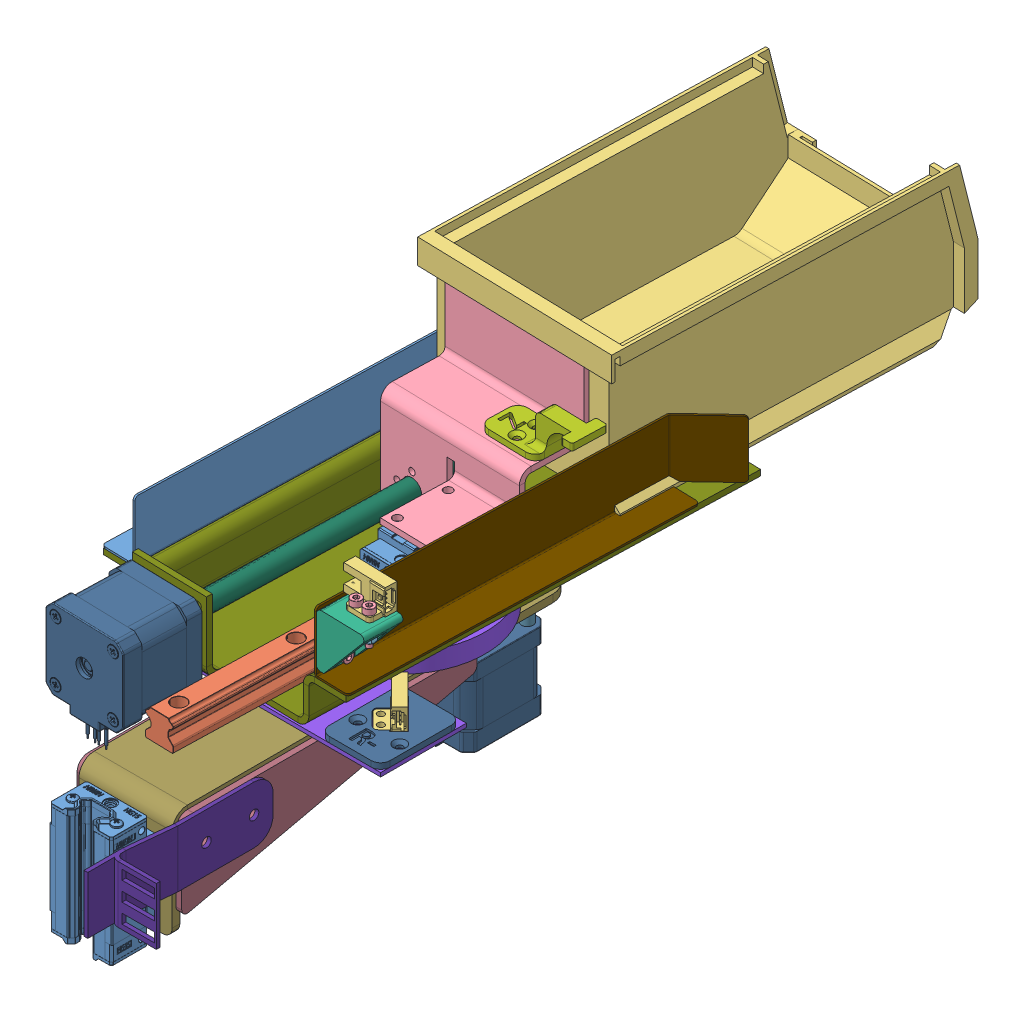
SolidWorks assembly T00003-000-R00, configuration Default. Lengths in mm.
Overall size (146.34 185.95 438.31).
45 component instances, 28 part files, 236 mates.
Components (placement in the parent):
- T00108-E00-R00-3: T00108-E00-R00 [Default] at (157.9488 862.2474 269.7743) x (1 0 0) z (0 1 0) size (34 23.7 61.49)
- T00110-E00-R00-1: T00110-E00-R00 [HGR15R400CE20] at (179.5179 918.7474 -31.6814) x (-0.999622 0 -0.027507) z (0.027507 0 -0.999622) size (15 15 270)
- T00108-E00-R00-4: T00108-E00-R00 [Default] at (176.1354 919.5474 91.2378) x (-0.999622 0 -0.027507) z (0.027507 0 -0.999622) size (34 23.7 61.49)
- T00148-E00-R00-1: T00148-E00-R00 [Default] at (211.9326 941.2474 40.4812) x (-0.999622 0 -0.027507) z (0.027507 0 -0.999622) size (104.77 76.2 187.32)
- T00126-000-R00-1: T00126-000-R00 [Default] at (176.1354 950.5474 91.2378) x (-0.999622 0 -0.027507) z (0 1 0) size (75 74 94)
- T00127-E00-R00-1: T00127-E00-R00 [DIN 625 - 6002 - 12,SI,NC,12_68] at (157.9488 901.2474 97.7743) x (0 1 0) z (0 0 1) size (9 32 32)
- T00128-0A4-R00-1: T00128-0A4-R00 [Default] at (157.9488 887.7474 97.7743) x (1 0 0) z (0 -1 0) size (25 25 21)
- T00129-E00-R00-1: T00129-E00-R00 [Circlip DIN 471 - 15 x 1.5] at (157.9488 905.9474 97.7743) x (0.837169 0 0.546944) z (0 -1 0) size (17.74 21.49 1.5)
- T00130-0A4-R01-1: T00130-0A4-R01 [Default] at (157.9488 895.7474 97.7743) x (0.027507 0 -0.999622) z (0 -1 0) size (90 90 20)
- T00132-E00-R00-4: T00132-E00-R00 [Metric - Spur gear 1M 60T 20PA 9FW ---S60N75H50L42N] at (157.9488 896.7474 97.7743) x (0 1 0) z (0 0 1) size (9 61.95 61.95)
- T00107-E00-R00-1: T00107-E00-R00 [Varsayılan] at (157.9488 879.7474 61.7743) x (-1 0 0) z (0 1 0) size (42 58.5 65.65)
- T00131-E00-R00-2: T00131-E00-R00 [Metric - Spur gear 1M 12T 20PA 8FW ---S12O10H14L5N] at (157.9488 896.7474 61.7743) x (0 1 0) z (0.924225 0 0.381849) size (14 13.61 13.61)
- T00133-0A4-R00-3: T00133-0A4-R00 [Default] at (157.9488 862.2474 237.7743) x (1 0 0) z (0 1 0) size (49 210 57)
- T00134-DXF-R00-1: T00134-DXF-R00 [Default] at (130.4488 892.7474 239.7743) x (0 0 -1) z (-1 0 0) size (155 44.25 3)
- T00134-DXF-R00-2: T00134-DXF-R00 [Default] at (182.4488 892.7474 239.7743) x (0 0 -1) z (-1 0 0) size (155 44.25 3)
- T00105-E00-R00-1: T00105-E00-R00 [Default] at (142.4488 890.7474 46.2743) x (1 0 0) z (0 -1 0) size (6 6 11)
- T00105-E00-R00-2: T00105-E00-R00 [Default] at (173.4488 890.7474 46.2743) x (0.974973 0 -0.222324) z (0 -1 0) size (6 6 11)
- T00105-E00-R00-3: T00105-E00-R00 [Default] at (142.4488 890.7474 77.2743) x (1 0 0) z (0 -1 0) size (6 6 11)
- T00105-E00-R00-4: T00105-E00-R00 [Default] at (173.4488 890.7474 77.2743) x (1 0 0) z (0 -1 0) size (6 6 11)
- T00107-E00-R00-2: T00107-E00-R00 [Varsayılan] at (132.7203 933.2474 196.6177) x (0.999622 0 0.027507) z (0.027507 0 -0.999622) size (42 58.5 65.65)
- T00111-E00-R00-1: T00111-E00-R00 [Default] at (139.377 933.2474 -45.2907) x (0.577812 0.816015 0.0159) z (0.815706 -0.578031 0.022446) size (10 240 10)
- T00135-DXF-R01-1: T00135-DXF-R01 [Default] at (158.3614 918.7474 82.78) x (-0.027507 0 0.999622) z (-0.999622 0 -0.027507) size (219 39 131)
- T00136-DXF-R01-1: T00136-DXF-R01 [Default] at (187.4488 877.7474 233.7743) x (0 0 -1) z (1 0 0) size (94.88 30 25)
- T00137-000-R00-1: T00137-000-R00 [gespiegeld] at (209.9194 941.2474 8.6701) x (0.027507 0 -0.999622) z (0.999622 0 0.027507) size (201.93 32 21.92)
- T00138-000-R00-1: T00138-000-R00 [gespiegeld] at (111.9565 941.2474 5.9745) x (0.027507 0 -0.999622) z (0.999622 0 0.027507) size (201.93 32 21.92)
- T00162-03D-R00-1: T00162-03D-R00 [Default] at (157.9488 905.7474 97.7743) x (0.027507 0 -0.999622) z (0 -1 0) size (22 26.53 4.1)
- T00153-E00-R00-4: T00153-E00-R00 [Default] at (207.435 977.2474 171.6635) x (0.027507 0 -0.999622) z (0 1 0) size (13 22.4 13.7)
- socket head cap screw_iso-1: socket head cap screw_iso [ISO 4762 M3 x 16 - 16N] at (223.2364 978.7474 179.1009) x (0 -1 0) z (0.997971 0 0.063667) size (19 5.5 5.5)
- hex nut style 1 gradeab_iso-1: hex nut style 1 gradeab_iso [ISO - 4032 - M3 - W - N] at (223.2364 965.2474 179.1009) x (1 0 0) z (0 1 0) size (5.5 6.35 2.4)
- socket head cap screw_iso-2: socket head cap screw_iso [ISO 4762 M3 x 16 - 16N] at (216.2391 978.7474 178.9084) x (0 -1 0) z (0 0 1) size (19 5.5 5.5)
- socket head cap screw_iso-3: socket head cap screw_iso [ISO 4762 M3 x 8 - 8N] at (212.2406 949.2474 178.7984) x (-0.999622 0 -0.027507) z (0.027393 0.090831 -0.995489) size (11 5.5 5.5)
- socket head cap screw_iso-4: socket head cap screw_iso [ISO 4762 M3 x 8 - 8N] at (212.2406 957.2474 178.7984) x (-0.999622 0 -0.027507) z (0.020371 -0.671964 -0.740304) size (11 5.5 5.5)
- hex nut style 1 gradeab_iso-3: hex nut style 1 gradeab_iso [ISO - 4032 - M3 - W - N] at (216.2391 965.4397 178.9084) x (0.95019 0 0.311672) z (0 1 0) size (5.5 6.35 2.4)
- hex nut style 1 gradeab_iso-4: hex nut style 1 gradeab_iso [ISO - 4032 - M3 - W - N] at (204.2436 957.2474 178.5783) x (0.020371 -0.671964 -0.740304) z (0.999622 0 0.027507) size (5.5 6.35 2.4)
- hex nut style 1 gradeab_iso-5: hex nut style 1 gradeab_iso [ISO - 4032 - M3 - W - N] at (204.2436 949.2474 178.5783) x (0.020371 -0.671964 -0.740304) z (0.999622 0 0.027507) size (5.5 6.35 2.4)
- socket head cap screw_iso-8: socket head cap screw_iso [ISO 4762 M4 x 10 - 10N] at (158.994 897.7474 59.7887) x (0 1 0) z (0.50631 0 0.862351) size (14 7 7)
- T00153-E00-R00-7: T00153-E00-R00 [Default] at (120.7549 900.9974 134.9681) x (0.707107 0 0.707107) z (0 1 0) size (13 22.4 13.7)
- T00153-E00-R00-8: T00153-E00-R00 [Default] at (195.1426 900.9974 134.9681) x (0.707107 0 -0.707107) z (0 1 0) size (13 22.4 13.7)
- socket head cap screw_iso-11: socket head cap screw_iso [ISO 4762 M3 x 6 - 6N] at (168.9902 898.7474 60.0638) x (0 1 0) z (0 0 1) size (9 5.5 5.5)
- socket head cap screw_iso-13: socket head cap screw_iso [ISO 4762 M3 x 6 - 6N] at (148.9978 898.7474 59.5136) x (0 1 0) z (-0.359477 0 -0.933154) size (9 5.5 5.5)
- T00168-03D-R00-2: T00168-03D-R00 [Default] at (205.2432 959.2474 178.6058) x (0.027507 0 -0.999622) z (0.999622 0 0.027507) size (20 28 25.65)
- T00163-03D-R00-1: T00163-03D-R00 [Default] at (179.6935 970.5474 52.8211) x (0.999622 0 0.027507) z (0 1 0) size (49 20 18.45)
- T00161-0A4-R00-2: T00161-0A4-R00 [Default] at (157.9488 894.7474 147.7835) size (125 2 45)
- T00164-03D-R00-1: T00164-03D-R00 [Default] at (157.9488 896.7474 147.7835) x (1 0 0) z (0 1 0) size (32 42.2 3)
- T00165-03D-R00-1: T00165-03D-R00 [Default] at (250.9488 896.7474 147.7835) x (1 0 0) z (0 1 0) size (32 42.2 3)
Mates (geometry in assembly coordinates):
- Coincident1: coincident: plane of ? through (170.4488 216.5018 364.6743) normal (1 0 0); plane of ? through (170.4488 228.5018 34.6743) normal (-1 0 0)
- Coincident2: coincident: plane of ? through (148.4488 238.5018 364.6743) normal (0 1 0); plane of ? through (170.4488 238.5018 394.6743) normal (0 1 0)
- Coincident3: coincident: plane of ? through (145.4488 216.5018 364.6743) normal (-1 0 0); plane of ? through (145.4488 223.5018 394.6743) normal (1 0 0)
- Coincident4: coincident: plane of ? through (148.4488 213.5018 364.6743) normal (0 -1 0); plane of ? through (142.4488 213.5018 34.6743) normal (0 -1 0)
- Coincident5: coincident: plane of ? through (142.4488 228.5018 404.6743) normal (0 0 1); plane of ? through (170.4488 223.5018 404.6743) normal (0 0 1)
- Width1: width: plane of ? through (142.4488 228.5018 404.6743) normal (0 0 1); plane of ? through (142.4488 228.5018 24.6743) normal (0 0 -1); plane of ? through (148.4488 216.5018 64.6743) normal (0 0 -1); plane of ? through (148.4488 216.5018 364.6743) normal (0 0 1)
- Concentric1: concentric: cylinder of ? through (142.4488 226.0018 394.6743) axis (1 0 0) radius 3.25; cylinder of ? through (157.9488 226.0018 394.6743) axis (-1 0 0) radius 3
- Concentric2: concentric: cylinder of ? through (142.4488 226.0018 34.6743) axis (1 0 0) radius 3.25; cylinder of ? through (157.9488 226.0018 34.6743) axis (-1 0 0) radius 3
- Width2: width: plane of ? through (168.9488 223.0018 34.6743) normal (1 0 0); plane of ? through (146.9488 219.0018 34.6743) normal (-1 0 0); plane of ? through (145.4488 223.5018 394.6743) normal (1 0 0); plane of ? through (170.4488 228.5018 34.6743) normal (-1 0 0)
- Width3: width: plane of ? through (168.9488 223.0127 394.9296) normal (1 0 0); plane of ? through (146.9488 219.0272 395.2699) normal (-1 0 0); plane of ? through (142.4488 223.5018 394.6743) normal (-1 0 0); plane of ? through (173.4488 228.5018 34.6743) normal (1 0 0)
- Tangent1: tangent: cylinder of ? through (157.9488 226.0018 -111.0344) axis (-1 0 0) radius 25; plane of ? through (135.9488 201.0018 1171.0489) normal (0 1 0)
- Tangent2: tangent: cylinder of ? through (157.9488 226.0018 -471.0344) axis (-1 0 0) radius 25; plane of ? through (135.9488 201.0018 1171.0489) normal (0 1 0)
- Width4: width: plane of ? through (173.4488 228.5018 -471.0344) normal (1 0 0); plane of ? through (142.4488 223.5018 -111.0344) normal (-1 0 0); plane of ? through (179.9488 201.0018 1171.0489) normal (-1 0 0); plane of ? through (135.9488 201.0018 1171.0489) normal (1 0 0)
- Width9: width: plane of ? through (172.9488 242.5018 314.4743) normal (1 0 0); plane of ? through (142.9488 242.5018 274.8743) normal (-1 0 0); plane of ? through (142.4488 223.5018 394.6743) normal (-1 0 0); plane of ? through (173.4488 228.5018 34.6743) normal (1 0 0)
- Coincident16: coincident: plane of ? through (148.1488 242.5018 269.6743) normal (0 0 -1); plane of ? through (150.9488 242.5018 269.6743) normal (0 0 1)
- Width10: width: plane of ? through (150.4488 833.0474 258.1086) normal (1 0 0); plane of ? through (165.4488 833.0474 258.1086) normal (-1 0 0); plane of ? through (150.4488 242.5018 258.0086) normal (-1 0 0); plane of ? through (165.4488 242.5018 258.0086) normal (1 0 0)
- Coincident18: coincident: plane of ? through (152.9073 834.5474 254.6743) normal (0 0 1); plane of ? through (162.9488 242.5018 254.6743) normal (0 0 -1)
- Width11: width: plane of ? through (172.9488 242.5018 314.4743) normal (1 0 0); plane of ? through (142.9488 242.5018 274.8743) normal (-1 0 0); plane of ? through (150.4488 242.5018 269.1743) normal (-1 0 0); plane of ? through (165.4488 242.5018 269.1743) normal (1 0 0)
- Coincident23: coincident: plane of T00110-E00-R00-1; plane of ? through (70.8326 930.4131 121.9122) normal (0.01567 0 -0.999877)
- Coincident24: coincident: plane of T00110-E00-R00-1 through (17.7623 933.7474 108.579) normal (0 1 0); plane of ? through (70.8718 933.7474 119.4125) normal (0 -1 0)
- Concentric5: concentric: circle of ?; cylinder of T00126-000-R00-1 through (87.3518 946.5474 101.6686) axis (0 1 0) radius 2.25
- Concentric6: concentric: circle of ?; cylinder of T00126-000-R00-1 through (86.9444 946.5474 127.6654) axis (0 1 0) radius 2.25
- Concentric8: concentric: cylinder of T00127-E00-R00-1 through (157.9488 880.6099 97.7743) axis (0 1 0) radius 7.5; cylinder of T00128-0A4-R00-1 through (157.9488 887.7474 97.7743) axis (0 -1 0) radius 7.5
- Coincident29: coincident: plane of T00127-E00-R00-1 through (147.8988 896.7474 97.7743) normal (0 -1 0); plane of T00128-0A4-R00-1 through (167.9488 896.7474 97.7743) normal (0 1 0)
- Concentric9: concentric: cylinder of T00128-0A4-R00-1 through (157.9488 887.7474 97.7743) axis (0 -1 0) radius 7.15; cylinder of T00129-E00-R00-1 through (157.9488 907.4474 97.7743) axis (0 -1 0) radius 7.15
- Coincident30: coincident: plane of T00128-0A4-R00-1 through (165.4488 905.9474 97.7743) normal (0 1 0); plane of T00129-E00-R00-1 through (157.9488 905.9474 97.7743) normal (0 -1 0)
- Concentric10: concentric: cylinder of T00127-E00-R00-1 through (157.9488 880.6099 97.7743) axis (0 1 0) radius 16; cylinder of T00130-0A4-R01-1 through (157.9488 895.7474 97.7743) axis (0 1 0) radius 16
- Coincident31: coincident: plane of T00127-E00-R00-1 through (142.2488 905.7474 97.7743) normal (0 1 0); plane of T00130-0A4-R01-1 through (158.3889 905.7474 81.7804) normal (0 -1 0)
- Concentric11: concentric: cylinder of T00130-0A4-R01-1 through (157.9488 895.7474 97.7743) axis (0 1 0) radius 21; cylinder of T00132-E00-R00-4 through (157.9488 946.7475 97.7743) axis (0 -1 0) radius 21
- Coincident32: coincident: plane of T00130-0A4-R01-1 through (158.5264 905.7474 76.7822) normal (0 -1 0); plane of T00132-E00-R00-4 through (157.9488 905.7474 97.7743) normal (0 1 0)
- Concentric12: concentric: cylinder of T00107-E00-R00-1 through (157.9488 904.7474 61.7743) axis (0 -1 0) radius 2.5; cylinder of T00131-E00-R00-2 through (157.9488 910.7475 61.7743) axis (0 -1 0) radius 2.5
- Coincident33: coincident: plane of T00107-E00-R00-1 through (159.9488 904.7474 61.7743) normal (0 1 0); plane of T00131-E00-R00-2 through (157.9488 904.7474 61.7743) normal (0 1 0)
- Distance5: distance = 1 mm: plane of T00131-E00-R00-2 through (157.9488 904.7474 61.7743) normal (0 1 0); plane of T00130-0A4-R01-1 through (158.5264 905.7474 76.7822) normal (0 -1 0)
- Coincident34: coincident: plane of T00108-E00-R00-3 through (173.9488 881.9474 241.7743) normal (0 0 -1); plane of T00133-0A4-R00-3 through (157.9488 862.2474 241.7743) normal (0 0 1)
- Concentric13: concentric: cylinder of T00108-E00-R00-3 through (144.9488 875.2474 241.7743) axis (0 0 -1) radius 1.65; cylinder of T00133-0A4-R00-3 through (144.9488 875.2474 241.7743) axis (0 0 -1) radius 2
- Concentric14: concentric: circle of T00108-E00-R00-3; cylinder of T00133-0A4-R00-3 through (170.9488 849.2474 241.7743) axis (0 0 -1) radius 2
- Coincident35: coincident: plane of T00128-0A4-R00-1 through (170.4488 890.7474 97.7743) normal (0 1 0); plane of T00133-0A4-R00-3 through (157.9488 890.7474 237.7743) normal (0 -1 0)
- Concentric15: concentric: cylinder of T00128-0A4-R00-1 through (157.9488 887.7474 97.7743) axis (0 -1 0) radius 12.5; cylinder of T00133-0A4-R00-3 through (157.9488 900.7474 97.7743) axis (0 -1 0) radius 10
- Concentric16: concentric: cone of T00107-E00-R00-1 through (142.4488 879.7474 46.2743) axis (0 -1 0); cylinder of T00133-0A4-R00-3 through (142.4488 894.7474 46.2743) axis (0 -1 0) radius 1.75
- Concentric17: concentric: circle of T00107-E00-R00-1; cylinder of T00133-0A4-R00-3 through (173.4488 894.7474 77.2743) axis (0 -1 0) radius 1.75
- Distance6: distance = 2 mm: plane of T00134-DXF-R00-2 through (185.4488 892.7474 233.7743) normal (0 1 0); plane of T00133-0A4-R00-3 through (157.9488 894.7474 237.7743) normal (0 1 0)
- Distance7: distance = 2 mm: plane of T00133-0A4-R00-3 through (157.9488 862.2474 241.7743) normal (0 0 1); plane of T00134-DXF-R00-2 through (185.4488 851.5004 239.7743) normal (0 0 1)
- Coincident39: coincident: plane of T00133-0A4-R00-3 through (182.4488 894.7474 31.7743) normal (1 0 0); plane of T00134-DXF-R00-2 through (182.4488 886.7474 233.7743) normal (-1 0 0)
- Coincident40: coincident: plane of T00133-0A4-R00-3 through (133.4488 894.7474 237.7743) normal (-1 0 0); plane of T00134-DXF-R00-1 through (133.4488 886.7474 233.7743) normal (1 0 0)
- Distance8: distance = 2 mm: plane of T00134-DXF-R00-1 through (133.4488 851.5004 239.7743) normal (0 0 1); plane of T00133-0A4-R00-3 through (157.9488 862.2474 241.7743) normal (0 0 1)
- Distance9: distance = 2 mm: plane of T00133-0A4-R00-3 through (157.9488 894.7474 237.7743) normal (0 1 0); plane of T00134-DXF-R00-1 through (133.4488 892.7474 233.7743) normal (0 1 0)
- Concentric18: concentric: cylinder of T00133-0A4-R00-3 through (173.4488 894.7474 46.2743) axis (0 -1 0) radius 1.75; cylinder of T00105-E00-R00-2 through (173.4488 879.7474 46.2743) axis (0 1 0) radius 1.75
- Coincident43: coincident: plane of T00107-E00-R00-1 through (157.9488 879.7474 61.7743) normal (0 1 0); plane of T00105-E00-R00-2 through (173.4488 879.7474 46.2743) normal (0 -1 0)
- Coincident44: coincident: plane of T00133-0A4-R00-3 through (157.9488 890.7474 237.7743) normal (0 -1 0); plane of T00105-E00-R00-1 through (142.4488 890.7474 46.2743) normal (0 1 0)
- Concentric19: concentric: cylinder of T00133-0A4-R00-3 through (142.4488 894.7474 46.2743) axis (0 -1 0) radius 1.75; cylinder of T00105-E00-R00-1 through (142.4488 879.7474 46.2743) axis (0 1 0) radius 1.75
- Coincident45: coincident: plane of T00133-0A4-R00-3 through (157.9488 890.7474 237.7743) normal (0 -1 0); plane of T00105-E00-R00-3 through (142.4488 890.7474 77.2743) normal (0 1 0)
- Concentric20: concentric: cylinder of T00133-0A4-R00-3 through (142.4488 894.7474 77.2743) axis (0 -1 0) radius 1.75; cylinder of T00105-E00-R00-3 through (142.4488 879.7474 77.2743) axis (0 1 0) radius 1.75
- Coincident46: coincident: plane of T00133-0A4-R00-3 through (157.9488 890.7474 237.7743) normal (0 -1 0); plane of T00105-E00-R00-4 through (173.4488 890.7474 77.2743) normal (0 1 0)
- Concentric21: concentric: cylinder of T00133-0A4-R00-3 through (173.4488 894.7474 77.2743) axis (0 -1 0) radius 1.75; cylinder of T00105-E00-R00-4 through (173.4488 879.7474 77.2743) axis (0 1 0) radius 1.75
- Coincident49: coincident: plane of T00110-E00-R00-1 through (165.5934 921.8332 238.0377) normal (-0.027507 0 0.999622); plane of T00107-E00-R00-2 through (131.6063 933.2474 237.1024) normal (-0.027507 0 0.999622)
- Concentric22: concentric: cylinder of T00107-E00-R00-2 through (133.408 933.2474 171.6272) axis (-0.027507 0 0.999622) radius 2.5; cylinder of T00111-E00-R00-1 through (133.6006 933.2474 164.6299) axis (-0.027507 0 0.999622) radius 2.5
- Coincident51: coincident: plane of T00107-E00-R00-2 through (132.7754 933.2474 194.6185) normal (0.027507 0 -0.999622); plane of T00111-E00-R00-1 through (132.7754 933.2474 194.6185) normal (-0.027507 0 0.999622)
- Coincident52: coincident: plane of T00130-0A4-R01-1 through (159.1866 915.7474 52.7913) normal (0 1 0); plane of T00135-DXF-R01-1 through (158.3614 915.7474 82.78) normal (0 -1 0)
- Coincident53: coincident: plane of T00110-E00-R00-1 through (179.0883 918.7474 238.409) normal (0 -1 0); plane of T00135-DXF-R01-1 through (158.3614 918.7474 82.78) normal (0 1 0)
- Distance11: distance = 3 mm: plane of T00107-E00-R00-2 through (132.7203 933.2474 196.6177) normal (0.027507 0 -0.999622); plane of T00135-DXF-R01-1 through (155.2943 918.7474 194.2378) normal (-0.027507 0 0.999622)
- Concentric23: concentric: cylinder of T00107-E00-R00-2 through (117.2262 948.7474 196.1914) axis (0.027507 0 -0.999622) radius 1.25; cylinder of T00135-DXF-R01-1 through (123.3327 948.7474 -25.7246) axis (-0.027507 0 0.999622) radius 1.75
- Concentric24: concentric: cylinder of T00107-E00-R00-2 through (148.2145 948.7474 197.0441) axis (0.027507 0 -0.999622) radius 1.25; cylinder of T00135-DXF-R01-1 through (154.321 948.7474 -24.8719) axis (-0.027507 0 0.999622) radius 1.75
- Coincident55: coincident: plane of T00148-E00-R00-1 through (217.0854 941.2474 -146.7729) normal (0 -1 0); plane of T00135-DXF-R01-1 through (158.3614 941.2474 82.78) normal (0 1 0)
- Width12: width: plane of T00148-E00-R00-1 through (113.164 941.2474 37.7634) normal (-0.999622 0 -0.027507); plane of T00148-E00-R00-1 through (205.9659 941.2474 40.317) normal (0.999622 0 0.027507); plane of T00135-DXF-R01-1 through (220.9621 941.2474 189.0421) normal (0.999622 0 0.027507); plane of T00135-DXF-R01-1 through (90.0117 941.2474 185.4387) normal (-0.999622 0 -0.027507)
- Coincident56: coincident: plane of T00148-E00-R00-1 through (211.9826 1014.7804 38.7039) normal (0.027507 0 -0.999622); plane of T00126-000-R00-1 through (177.6071 950.5474 37.758) normal (-0.027507 0 0.999622)
- Coincident62: coincident: plane of ? through (148.4488 238.5018 364.6743) normal (0 1 0); plane of ? through (100.4488 238.5018 294.6743) normal (0 -1 0)
- Width15: width: plane of ? through (142.9488 242.5018 224.6743) normal (-1 0 0); plane of ? through (172.9488 242.5018 364.6743) normal (1 0 0); plane of ? through (142.4488 223.5018 394.6743) normal (-1 0 0); plane of ? through (173.4488 228.5018 34.6743) normal (1 0 0)
- Coincident63: coincident: plane of ? through (148.4488 216.5018 364.6743) normal (0 0 1); plane of ? through (57.9488 242.5018 364.6743) normal (0 0 1)
- Width16: width: plane of ? through (57.9488 242.5018 364.6743) normal (0 0 1); plane of ? through (57.9488 242.5018 224.6743) normal (0 0 -1); plane of ? through (148.1488 242.5018 269.6743) normal (0 0 -1); plane of ? through (167.7488 242.5018 319.6743) normal (0 0 1)
- Coincident64: coincident: plane of ? through (164.4488 242.5018 266.5885) normal (0 -1 0); plane of ? through (100.4488 242.5018 294.6743) normal (0 1 0)
- Coincident65: coincident: plane of ? through (167.7488 242.5018 314.4743) normal (0 -1 0); plane of ? through (100.4488 242.5018 294.6743) normal (0 1 0)
- Coincident70: coincident: plane of ? through (82.9488 242.5018 294.6743) normal (0 -1 0); plane of ? through (100.4488 242.5018 294.6743) normal (0 1 0)
- Concentric28: concentric: cylinder of ? through (82.9488 248.5018 339.6743) axis (0 1 0) radius 6; cylinder of ? through (82.9488 242.5018 339.6743) axis (0 -1 0) radius 6.25
- Concentric29: concentric: cylinder of ? through (82.9488 248.5018 249.6743) axis (0 1 0) radius 6; cylinder of ? through (82.9488 242.5018 249.6743) axis (0 -1 0) radius 6.25
- Coincident74: coincident: plane of T00130-0A4-R01-1 through (157.9488 895.7474 97.7743) normal (0.999622 0 0.027507); plane of T00135-DXF-R01-1 through (158.3614 918.7474 82.78) normal (-0.999622 0 -0.027507)
- Distance14: distance = 15 mm: plane of T00135-DXF-R01-1 through (158.3614 918.7474 82.78) normal (-0.027507 0 0.999622); plane of T00130-0A4-R01-1 through (157.9488 895.7474 97.7743) normal (0.027507 0 -0.999622)
- LimitDistance1: limit distance = 51.7728 mm: plane of ? through (69.531 925.1631 109.2402) normal (-0.999877 0 -0.01567); plane of T00110-E00-R00-1
- LimitAngle1: limit planar angle = 0 rad: plane of T00135-DXF-R01-1 through (203.8442 918.7474 84.0315) normal (0.999622 0 0.027507); plane of T00133-0A4-R00-3 through (133.4488 894.7474 31.7743) normal (0 0 -1)
- LimitDistance2: limit distance = 589.0457 mm: plane of ? through (100.4488 242.5018 294.6743) normal (0 1 0); plane of ? through (163.0988 831.5474 263.3586) normal (0 -1 0)
- LimitDistance3: limit distance = 1272.0833 mm: plane of ? through (170.4488 223.5018 -101.0344) normal (0 0 1); plane of ? through (157.9488 198.0018 1171.0489) normal (0 0 1)
- Coincident103: coincident: plane of ? through (132.9488 198.0018 1171.0489) normal (-1 0 0); plane of ? through (132.9488 203.0018 1171.0489) normal (-1 0 0)
- Coincident104: coincident: plane of ? through (157.9488 198.0018 1171.0489) normal (0 0 1); plane of ? through (137.9488 203.0018 1171.0489) normal (0 0 -1)
- Coincident105: coincident: plane of ? through (132.9488 198.0018 1171.0489) normal (0 -1 0); plane of ? through (137.9488 198.0018 1171.0489) normal (0 -1 0)
- Coincident106: coincident: plane of ? through (132.9488 198.0018 1171.0489) normal (-1 0 0); plane of ? through (132.9488 203.0018 -564.9511) normal (-1 0 0)
- Coincident107: coincident: plane of ? through (157.9488 198.0018 -560.9511) normal (0 0 -1); plane of ? through (137.9488 203.0018 -560.9511) normal (0 0 1)
- Coincident108: coincident: plane of ? through (132.9488 198.0018 1171.0489) normal (0 -1 0); plane of ? through (137.9488 198.0018 -564.9511) normal (0 -1 0)
- Distance26: distance = 1 mm: plane of ? through (117.9488 237.5018 249.6743) normal (0 1 0); plane of ? through (100.4488 238.5018 294.6743) normal (0 -1 0)
- Concentric55: concentric: circle of ?; cylinder of ? through (112.9488 234.0018 249.6743) axis (0 1 0) radius 11
- Coincident125: coincident: plane of ? through (123.9488 230.5018 249.6743) normal (0 -1 0); plane of ? through (117.9488 230.5018 249.6743) normal (0 1 0)
- Concentric56: concentric: cylinder of ? through (112.9488 234.0018 249.6743) axis (0 1 0) radius 11; cylinder of ? through (112.9488 227.0018 249.6743) axis (0 1 0) radius 11
- Distance27: distance = 1 mm: plane of ? through (108.7629 237.5018 336.9396) normal (0 1 0); plane of ? through (100.4488 238.5018 294.6743) normal (0 -1 0)
- Concentric57: concentric: cylinder of ? through (112.9488 242.5018 339.6743) axis (0 -1 0) radius 4.25; cylinder of ? through (112.9488 234.0018 339.6743) axis (0 -1 0) radius 11
- Coincident127: coincident: plane of ? through (108.7629 230.5018 336.9396) normal (0 -1 0); plane of ? through (103.7399 230.5018 333.6579) normal (0 1 0)
- Concentric58: concentric: cylinder of ? through (112.9488 234.0018 339.6743) axis (0 -1 0) radius 11; cylinder of ? through (112.9488 227.0018 339.6743) axis (0 -1 0) radius 11
- Concentric59: concentric: cylinder of ? through (82.9488 208.9018 -211.0344) axis (0 1 0) radius 7.5; cylinder of ? through (82.9488 1416.5905 -211.0344) axis (0 1 0) radius 7.5
- Distance28: distance = 1 mm: plane of ? through (105.5523 237.5018 -196.2669) normal (0 1 0); plane of ? through (100.4488 238.5018 -211.0344) normal (0 -1 0)
- Coincident133: coincident: plane of T00134-DXF-R00-2 through (185.4488 892.7474 233.7743) normal (0 1 0); plane of T00136-DXF-R01-1 through (185.4488 892.7474 273.7743) normal (0 1 0)
- Coincident134: coincident: plane of T00134-DXF-R00-2 through (185.4488 886.7474 233.7743) normal (1 0 0); plane of T00136-DXF-R01-1 through (185.4488 877.7474 233.7743) normal (-1 0 0)
- Concentric63: concentric: cylinder of T00134-DXF-R00-2 through (175.4488 877.7474 203.7743) axis (1 0 0) radius 2.75; cylinder of T00136-DXF-R01-1 through (185.4488 877.7474 203.7743) axis (1 0 0) radius 2.5
- Coincident135: coincident: plane of ? through (172.9488 242.5018 314.4743) normal (1 0 0); plane of ? through (172.9488 266.0484 296.2234) normal (-1 0 0)
- Concentric68: concentric: cylinder of ? through (209.3488 260.2518 294.6743) axis (1 0 0) radius 6; cylinder of ? through (-989.14 260.2518 294.6743) axis (-1 0 0) radius 7.5
- Distance33: distance = 17 mm: plane of ? through (189.9488 282.6397 279.5818) normal (-1 0 0); plane of ? through (172.9488 242.5018 314.4743) normal (1 0 0)
- Lock1: lock: unknown of ?; unknown of ?
- Coincident136: coincident: plane of T00110-E00-R00-1 through (179.0883 918.7474 238.409) normal (0 -1 0); plane of T00135-DXF-R01-1 through (158.3614 918.7474 82.78) normal (0 1 0)
- Concentric77: concentric: cylinder of T00126-000-R00-1 through (136.4897 933.2474 59.6353) axis (-0.027507 0 0.999622) radius 5.25; cylinder of T00111-E00-R00-1 through (132.7754 933.2474 194.6185) axis (0.027507 0 -0.999622) radius 5
- Coincident137: coincident: plane of T00135-DXF-R01-1 through (158.3614 941.2474 82.78) normal (0 1 0); plane of T00137-000-R00-1 through (209.9194 941.2474 8.6701) normal (0 -1 0)
- Distance34: distance = 1 mm: plane of T00135-DXF-R01-1 through (220.9621 941.2474 189.0421) normal (0.999622 0 0.027507); plane of T00137-000-R00-1 through (221.9617 941.2474 189.0696) normal (0.999622 0 0.027507)
- Distance35: distance = 32 mm: plane of T00137-000-R00-1 through (226.913 941.2474 9.1378) normal (0.027507 0 -0.999622); plane of T00135-DXF-R01-1 through (226.7936 941.2474 -22.8776) normal (0.027507 0 -0.999622)
- Coincident140: coincident: plane of T00135-DXF-R01-1 through (158.3614 941.2474 82.78) normal (0 1 0); plane of T00138-000-R00-1 through (111.9565 941.2474 5.9745) normal (0 -1 0)
- Distance36: distance = 1 mm: plane of T00135-DXF-R01-1 through (90.0117 941.2474 185.4387) normal (-0.999622 0 -0.027507); plane of T00138-000-R00-1 through (89.0121 941.2474 185.4112) normal (-0.999622 0 -0.027507)
- Distance37: distance = 32 mm: plane of T00138-000-R00-1 through (93.9633 941.2474 5.4793) normal (0.027507 0 -0.999622); plane of T00135-DXF-R01-1 through (95.8432 941.2474 -26.481) normal (0.027507 0 -0.999622)
- Concentric78: concentric: circle of T00108-E00-R00-4; cylinder of T00126-000-R00-1 through (162.7828 947.5474 103.8753) axis (0 1 0) radius 2.25
- Concentric80: concentric: circle of T00108-E00-R00-4; cylinder of T00126-000-R00-1 through (189.4881 947.5474 78.6003) axis (0 1 0) radius 2.25
- Coincident142: coincident: plane of T00108-E00-R00-4 through (160.6834 947.5474 71.1051) normal (0 1 0); plane of T00126-000-R00-1 through (176.1354 947.5474 91.2378) normal (0 -1 0)
- Width17: width: plane of T00108-E00-R00-4 through (180.0804 925.9631 120.5574) normal (-0.999622 0 -0.027507); plane of T00108-E00-R00-4 through (170.584 925.9631 120.2961) normal (0.999622 0 0.027507); plane of T00110-E00-R00-1 through (179.5881 919.2474 238.4228) normal (0.999622 0 0.027507); plane of T00110-E00-R00-1 through (164.5938 919.2474 238.0102) normal (-0.999622 0 -0.027507)
- Concentric81: concentric: circle of T00108-E00-R00-3; cylinder of T00133-0A4-R00-3 through (144.9488 875.2474 241.7743) axis (0 0 -1) radius 2
- Concentric82: concentric: circle of T00108-E00-R00-3; cylinder of T00133-0A4-R00-3 through (170.9488 849.2474 241.7743) axis (0 0 -1) radius 2
- Coincident144: coincident: plane of T00108-E00-R00-3 through (173.9488 881.9474 241.7743) normal (0 0 -1); plane of T00133-0A4-R00-3 through (157.9488 862.2474 241.7743) normal (0 0 1)
- Coincident145: coincident: plane of T00136-DXF-R01-1 through (182.9675 877.7474 233.6502) normal (-1 0 0); circle of ?
- Parallel1: parallel: line of T00136-DXF-R01-1 through (184.9675 892.7474 303.6502) axis (0 0 -1); line of ? through (182.9675 887.2474 281.5502) axis (0 0 1)
- Width18: width: plane of T00136-DXF-R01-1 through (184.9675 892.7474 303.6502) normal (0 0 1); plane of T00136-DXF-R01-1 through (184.9675 877.7474 275.6502) normal (0 0 1); plane of ? through (184.4675 900.2474 300.8502) normal (0 0 1); plane of ? through (180.7675 900.2474 278.4502) normal (0 0 -1)
- Distance38: distance = 1 mm: plane of ? through (182.0675 893.7474 286.7502) normal (0 -1 0); plane of T00136-DXF-R01-1 through (187.9675 892.7474 270.6502) normal (0 1 0)
- Coincident146: coincident: plane of T00136-DXF-R01-1 through (184.9675 877.7474 233.7743) normal (1 0 0); plane of ? through (184.9675 879.8974 301.3502) normal (-1 0 0)
- Distance39: distance = 19 mm: plane of T00136-DXF-R01-1 through (184.9675 877.7474 275.6502) normal (0 0 1); moEndPointRef_w of ?
- Parallel2: parallel: line of T00136-DXF-R01-1 through (184.9675 862.7474 303.6502) axis (0 1 0); line of ? through (184.9675 889.0974 301.3502) axis (0 -1 0)
- Width19: width: plane of T00136-DXF-R01-1 through (187.9675 862.7474 270.6502) normal (0 -1 0); plane of T00136-DXF-R01-1 through (187.9675 892.7474 270.6502) normal (0 1 0); plane of ? through (190.9675 889.0974 287.9502) normal (0 1 0); plane of ? through (187.4675 866.3974 301.3502) normal (0 -1 0)
- Coincident147: coincident: plane of T00133-0A4-R00-3 through (157.9488 894.7474 237.7743) normal (0 1 0); plane of ? through (132.9488 894.7474 61.7743) normal (0 -1 0)
- Width20: width: plane of T00133-0A4-R00-3 through (182.4488 894.7474 31.7743) normal (1 0 0); plane of T00133-0A4-R00-3 through (133.4488 894.7474 237.7743) normal (-1 0 0); plane of ? through (182.9488 894.7474 61.7743) normal (-1 0 0); plane of ? through (132.9488 894.7474 61.7743) normal (1 0 0)
- Coincident148: coincident: plane of T00133-0A4-R00-3 through (133.4488 894.7474 31.7743) normal (0 0 -1); plane of ? through (157.9488 894.7474 31.7743) normal (0 0 -1)
- InPlace1: in place: plane of ? through (178.9488 905.7474 97.7743) normal (0 -1 0); plane of ? through (0 905.7474 0) normal (0 -1 0); moOrthogonalPlaneRef_w of ? through (178.9488 905.7474 97.7743) normal (0 -1 0); plane of ? through (0 905.7474 0) normal (0 0 -1); plane of ? through (178.9488 905.7474 97.7743) normal (0 -1 0); plane of ? through (0 905.7474 0) normal (-1 0 0); plane of T00130-0A4-R01-1 through (158.5264 905.7474 76.7822) normal (0 -1 0); unknown of T00162-03D-R00-1
- Coincident153: coincident: plane of T00130-0A4-R01-1; plane of T00162-03D-R00-1
- Coincident154: coincident: line of T00130-0A4-R01-1 through (157.9488 905.7474 97.7743) axis (0.999622 0 0.027507); plane of T00162-03D-R00-1 through (157.9488 905.7474 97.7743) normal (0.999622 0 0.027507)
- Coincident155: coincident: unknown of T00130-0A4-R01-1; plane of T00162-03D-R00-1 through (157.9488 905.7474 97.7743) normal (0.027507 0 -0.999622)
- Coincident156: coincident: plane of T00130-0A4-R01-1 through (168.0287 905.7474 116.197) normal (0 -1 0); plane of ? through (157.9488 905.7474 97.7743) normal (0 1 0)
- Concentric83: concentric: cylinder of T00130-0A4-R01-1 through (139.9489 905.7474 64.8767) axis (0 -1 0) radius 2.1; cylinder of ? through (139.9489 901.7474 64.8767) axis (0 1 0) radius 2.25
- Coincident157: coincident: unknown of ?; unknown of ?
- InPlace2: in place: plane of T00134-DXF-R00-2 through (185.4488 886.7474 233.7743) normal (1 0 0); plane of ? through (185.4488 0 0) normal (1 0 0); plane of T00134-DXF-R00-2 through (185.4488 886.7474 233.7743) normal (1 0 0); plane of ? through (185.4488 0 0) normal (0 1 0); plane of T00134-DXF-R00-2 through (185.4488 886.7474 233.7743) normal (1 0 0); plane of ? through (185.4488 0 0) normal (0 0 -1); plane of T00134-DXF-R00-2 through (185.4488 886.7474 233.7743) normal (1 0 0); unknown of ?
- Coincident165: coincident: plane of T00134-DXF-R00-2; plane of ?
- Coincident166: coincident: plane of T00134-DXF-R00-2 through (185.4488 892.7474 239.7743) normal (0 -1 0); plane of ? through (185.4488 892.7474 239.7743) normal (0 -1 0)
- Coincident167: coincident: plane of T00134-DXF-R00-2 through (185.4488 892.7474 239.7743) normal (0 0 -1); plane of ? through (185.4488 892.7474 239.7743) normal (0 0 1)
- Coincident173: coincident: plane of T00134-DXF-R00-2 through (185.4488 886.7474 233.7743) normal (1 0 0); plane of ? through (185.4488 890.7474 97.2743) normal (-1 0 0)
- Distance44: distance = 15 mm: plane of T00134-DXF-R00-2 through (185.4488 889.7474 84.7743) normal (0 0 -1); plane of ? through (185.4488 879.7474 69.7743) normal (0 0 -1)
- Coincident175: coincident: plane of T00134-DXF-R00-2 through (185.4488 892.7474 233.7743) normal (0 1 0); plane of ? through (212.9488 892.7474 97.2743) normal (0 1 0)
- Width21: width: plane of ? through (240.4488 892.7474 124.7743) normal (0 0 1); plane of ? through (240.4488 892.7474 69.7743) normal (0 0 -1); plane of ? through (215.4488 896.9974 77.2743) normal (0 0 -1); plane of ? through (215.4488 896.9974 117.2743) normal (0 0 1)
- Coincident176: coincident: plane of ? through (212.9488 892.7474 97.2743) normal (0 1 0); plane of ? through (235.4488 892.7474 112.2743) normal (0 -1 0)
- Coincident177: coincident: plane of T00138-000-R00-1; plane of ? through (142.7292 957.2474 4.8288) normal (-0.746359 0 0.665543)
- Coincident178: coincident: plane of T00138-000-R00-1 through (255.8716 971.2474 131.7099) normal (0 1 0); plane of ? through (171.7754 971.2474 -7.6739) normal (0 1 0)
- Coincident179: coincident: plane of ? through (171.7754 971.2474 -7.6739) normal (0 1 0); plane of T00153-E00-R00-4 through (149.8068 971.2474 -14.8808) normal (0 -1 0)
- Width22: width: plane of ? through (171.7754 943.2474 -7.6739) normal (0.665543 0 0.746359); plane of ? through (158.4645 943.2474 -22.6011) normal (-0.665543 0 -0.746359); axis of ? through (154.8949 971.2474 -6.0195) axis (0 1 0)
- Concentric84: concentric: cylinder of T00153-E00-R00-4 through (223.2364 973.2474 179.1009) axis (0 1 0) radius 1.75; cylinder of socket head cap screw_iso-1 through (223.2364 1010.4974 179.1009) axis (0 1 0) radius 1.5
- Coincident182: coincident: plane of T00153-E00-R00-4 through (225.6107 975.7474 169.1625) normal (0 1 0); plane of socket head cap screw_iso-1 through (223.4115 975.7474 176.3565) normal (0 -1 0)
- Coincident183: coincident: plane of ? through (117.2278 963.2474 -29.7794) normal (0 -1 0); plane of hex nut style 1 gradeab_iso-1 through (154.8949 963.2474 -9.195) normal (0 1 0)
- Concentric85: concentric: cylinder of socket head cap screw_iso-1 through (223.2364 1010.4974 179.1009) axis (0 1 0) radius 1.5; cylinder of hex nut style 1 gradeab_iso-1 through (223.2364 962.8474 179.1009) axis (0 1 0) radius 1.25
- Coincident184: coincident: plane of T00153-E00-R00-4 through (225.6107 975.7474 169.1625) normal (0 1 0); plane of socket head cap screw_iso-2 through (218.9891 975.7474 178.9084) normal (0 -1 0)
- Concentric86: concentric: cylinder of T00153-E00-R00-4 through (216.2391 973.2474 178.9084) axis (0 1 0) radius 1.75; cylinder of socket head cap screw_iso-2 through (216.2391 1010.4974 178.9084) axis (0 1 0) radius 1.5
- Concentric87: concentric: cylinder of socket head cap screw_iso-2 through (216.2391 1010.4974 178.9084) axis (0 1 0) radius 1.5; cylinder of hex nut style 1 gradeab_iso-3 through (216.2391 963.0397 178.9084) axis (0 1 0) radius 1.25
- Coincident185: coincident: plane of ? through (117.2278 963.2474 -29.7794) normal (0 -1 0); plane of hex nut style 1 gradeab_iso-3 through (151.4071 963.2474 -4.0191) normal (0 1 0)
- Coincident186: coincident: plane of T00168-03D-R00-2 through (210.3761 965.2474 137.4904) normal (0.999622 0 0.027507); plane of socket head cap screw_iso-4 through (209.2926 959.284 176.8686) normal (-0.999622 0 -0.027507)
- Concentric88: concentric: cylinder of ? through (142.7292 955.2474 4.8288) axis (0.746359 0 -0.665543) radius 1.8; cylinder of socket head cap screw_iso-4 through (171.6506 955.2474 -20.961) axis (0.746359 0 -0.665543) radius 1.5
- Concentric91: concentric: cylinder of ? through (142.7292 947.2474 4.8288) axis (0.746359 0 -0.665543) radius 1.8; cylinder of socket head cap screw_iso-3 through (171.6506 947.2474 -20.961) axis (0.746359 0 -0.665543) radius 1.5
- Coincident187: coincident: plane of T00168-03D-R00-2 through (210.3761 965.2474 137.4904) normal (0.999622 0 0.027507); plane of socket head cap screw_iso-3 through (209.2348 951.9861 178.9655) normal (-0.999622 0 -0.027507)
- Coincident188: coincident: plane of T00137-000-R00-1 through (208.9198 941.2474 8.6426) normal (-0.999622 0 -0.027507); plane of hex nut style 1 gradeab_iso-4 through (204.3023 959.5991 176.4453) normal (0.999622 0 0.027507)
- Concentric92: concentric: cylinder of socket head cap screw_iso-4 through (243.9786 957.2474 179.6717) axis (0.999622 0 0.027507) radius 1.5; cylinder of hex nut style 1 gradeab_iso-4 through (201.8445 957.2474 178.5123) axis (0.999622 0 0.027507) radius 1.25
- Coincident189: coincident: plane of T00137-000-R00-1 through (208.9198 941.2474 8.6426) normal (-0.999622 0 -0.027507); plane of hex nut style 1 gradeab_iso-5 through (204.3023 951.5991 176.4453) normal (0.999622 0 0.027507)
- Concentric93: concentric: cylinder of socket head cap screw_iso-3 through (243.9786 949.2474 179.6717) axis (0.999622 0 0.027507) radius 1.5; circle of hex nut style 1 gradeab_iso-5
- Coincident190: coincident: plane of T00138-000-R00-1; plane of ? through (158.4645 943.2474 -22.6011) normal (-0.665543 0 -0.746359)
- Coincident191: coincident: plane of ? through (240.4488 892.7474 124.7743) normal (1 0 0); plane of ? through (240.4488 896.9974 112.2743) normal (1 0 0)
- Coincident192: coincident: plane of T00162-03D-R00-1 through (157.9488 901.7474 97.7743) normal (0 -1 0); plane of socket head cap screw_iso-8 through (155.9758 901.7474 61.5608) normal (0 1 0)
- Concentric94: concentric: cylinder of T00162-03D-R00-1 through (158.994 901.7474 59.7887) axis (0 1 0) radius 2.25; cylinder of socket head cap screw_iso-8 through (158.994 865.9974 59.7887) axis (0 -1 0) radius 2
- Distance43: distance = 52.5 mm: unknown of ?; line of T00127-E00-R00-1 through (157.9488 908.857 97.7743) axis (0 -1 0)
- Coincident196: coincident: plane of ? through (109.8842 896.9974 45.1603) normal (0 -1 0); plane of ? through (215.4488 896.9974 74.5623) normal (0 1 0)
- Symmetric1: symmetric: plane of ? through (117.4048 900.9974 54.123) normal (-0.766044 0 0.642788); plane of ? through (122.001 900.9974 50.2663) normal (0.766044 0 -0.642788)
- Width23: width: plane of T00162-03D-R00-1 through (157.9488 905.7474 97.7743) normal (0 1 0); plane of T00162-03D-R00-1 through (157.9488 902.2474 97.7743) normal (0 -1 0); plane of ? through (122.8042 906.9974 60.5578) normal (0 -1 0); plane of ? through (117.4048 900.9974 54.123) normal (0 1 0)
- Coincident199: coincident: plane of T00134-DXF-R00-2 through (185.4488 886.7474 233.7743) normal (1 0 0); plane of ? through (185.4488 890.7474 104.7743) normal (-1 0 0)
- Coincident201: coincident: plane of T00134-DXF-R00-2 through (185.4488 889.7474 84.7743) normal (0 0 -1); plane of ? through (185.4488 874.7474 84.7743) normal (0 0 -1)
- Coincident202: coincident: plane of ? through (215.4488 892.7474 74.5623) normal (0 -1 0); plane of ? through (212.9488 892.7474 104.7743) normal (0 1 0)
- Coincident203: coincident: plane of ? through (240.4488 896.9974 74.5623) normal (1 0 0); plane of ? through (240.4488 892.7474 124.7743) normal (1 0 0)
- Coincident206: coincident: plane of T00134-DXF-R00-1 through (130.4488 886.7474 233.7743) normal (-1 0 0); plane of ? through (130.4488 890.7474 104.7743) normal (1 0 0)
- Coincident207: coincident: plane of ? through (240.4488 892.7474 84.7743) normal (0 0 -1); plane of ? through (75.4488 892.7474 84.7743) normal (0 0 -1)
- Coincident208: coincident: plane of ? through (212.9488 892.7474 104.7743) normal (0 1 0); plane of ? through (102.9488 892.7474 104.7743) normal (0 1 0)
- Coincident209: coincident: plane of ? through (102.9488 892.7474 104.7743) normal (0 1 0); plane of ?
- Coincident210: coincident: plane of ? through (75.4488 892.7474 84.7743) normal (-1 0 0); plane of ?
- Coincident211: coincident: plane of ? through (75.4488 892.7474 84.7743) normal (0 0 -1); plane of ?
- Coincident212: coincident: plane of ? through (192.1446 889.9953 76.9058) normal (0.206766 0.946852 -0.246414); unknown of ?
- Symmetric2: symmetric: plane of ? through (131.1874 900.6377 134.3344) normal (0.766044 0 0.642788); plane of ? through (126.5912 900.6377 130.4777) normal (-0.766044 0 -0.642788)
- Distance46: distance = 52.2 mm: line of T00127-E00-R00-1 through (157.9488 908.857 97.7743) axis (0 -1 0); unknown of ?
- Width24: width: plane of T00162-03D-R00-1 through (157.9488 905.7474 97.7743) normal (0 1 0); plane of T00162-03D-R00-1 through (157.9488 902.2474 97.7743) normal (0 -1 0); plane of T00153-E00-R00-7 through (124.2905 906.9974 135.6752) normal (0 -1 0); plane of T00153-E00-R00-7 through (118.3508 900.9974 141.6149) normal (0 1 0)
- Symmetric3: symmetric: plane of T00153-E00-R00-7 through (114.1081 900.9974 137.3723) normal (-0.707107 0 -0.707107); plane of T00153-E00-R00-7 through (118.3508 900.9974 141.6149) normal (0.707107 0 0.707107)
- Distance47: distance = 52 mm: unknown of T00153-E00-R00-7; line of T00128-0A4-R00-1 through (157.9488 905.9474 97.7743) axis (0 -1 0)
- Width25: width: plane of T00153-E00-R00-8 through (201.7894 900.9974 137.3723) normal (0 1 0); plane of T00153-E00-R00-8 through (195.8497 906.9974 131.4326) normal (0 -1 0); plane of T00162-03D-R00-1 through (157.9488 905.7474 97.7743) normal (0 1 0); plane of T00162-03D-R00-1 through (157.9488 902.2474 97.7743) normal (0 -1 0)
- Symmetric4: symmetric: plane of T00153-E00-R00-8 through (201.7894 900.9974 137.3723) normal (0.707107 0 -0.707107); plane of T00153-E00-R00-8 through (197.5467 900.9974 141.6149) normal (-0.707107 0 0.707107)
- Distance48: distance = 52 mm: unknown of T00153-E00-R00-8; line of T00130-0A4-R01-1 through (157.9488 905.7474 97.7743) axis (0 1 0)
- InPlace3: in place: plane of ? through (157.9488 896.7474 148.0532) normal (0 1 0); plane of ? through (0 896.7474 0) normal (0 1 0); plane of ? through (157.9488 896.7474 148.0532) normal (0 1 0); plane of ? through (0 896.7474 0) normal (0 0 -1); plane of ? through (157.9488 896.7474 148.0532) normal (0 1 0); plane of ? through (0 896.7474 0) normal (1 0 0); plane of ? through (-456.6296 235.5306 -359.6309) normal (-0.293076 0.910062 -0.293076); unknown of ?
- Coincident214: coincident: plane of ?; plane of T00164-03D-R00-1
- Coincident215: coincident: unknown of ?; unknown of ?
- Coincident216: coincident: unknown of ?; unknown of ?
- Distance49: distance = 0.25 mm: plane of T00153-E00-R00-7 through (108.4513 897.2974 151.5144) normal (-0.707107 0 0.707107); plane of T00164-03D-R00-1 through (108.4513 899.7474 151.868) normal (0.707107 0 -0.707107)
- Coincident219: coincident: plane of ? through (-456.6296 235.5306 -359.6309) normal (-0.293076 0.910062 -0.293076); plane of T00165-03D-R00-1
- Coincident220: coincident: plane of ? through (-395.9284 247.2536 -383.9297) normal (0.044969 -0.293076 -0.955031); plane of T00165-03D-R00-1
- Coincident221: coincident: plane of ? through (-515.3072 210.6191 -378.3086) normal (-0.955031 -0.293076 0.044969); plane of T00165-03D-R00-1
- Concentric97: concentric: cylinder of T00161-0A4-R00-2 through (167.9488 886.7474 140.2835) axis (0 1 0) radius 2.25; cylinder of ? through (167.9488 932.4974 140.2835) axis (0 1 0) radius 3.5
- Coincident222: coincident: plane of T00161-0A4-R00-2; plane of ? through (171.4488 896.7474 140.2835) normal (0 -1 0)
- Coincident223: coincident: plane of T00153-E00-R00-8 through (211.6889 897.2974 147.2718) normal (0.707107 0 0.707107); plane of ? through (232.9394 911.031 126.0212) normal (-0.707107 0 -0.707107)
- Concentric98: concentric: cylinder of T00162-03D-R00-1 through (168.9902 901.7474 60.0638) axis (0 1 0) radius 1.75; cylinder of socket head cap screw_iso-11 through (168.9902 866.9974 60.0638) axis (0 -1 0) radius 1.5
- Coincident226: coincident: plane of T00162-03D-R00-1 through (157.9488 901.7474 97.7743) normal (0 -1 0); circle of socket head cap screw_iso-11
- Coincident229: coincident: plane of T00162-03D-R00-1 through (157.9488 901.7474 97.7743) normal (0 -1 0); plane of socket head cap screw_iso-13 through (151.564 901.7474 58.5251) normal (0 1 0)
- Concentric100: concentric: cylinder of T00162-03D-R00-1 through (148.9978 901.7474 59.5136) axis (0 1 0) radius 1.75; cylinder of socket head cap screw_iso-13 through (148.9978 866.9974 59.5136) axis (0 -1 0) radius 1.5
- Coincident230: coincident: plane of ? through (-456.6296 235.5306 -359.6309) normal (-0.293076 0.910062 -0.293076); plane of ? through (74.4309 575.6434 165.4295) normal (0.293076 -0.910062 0.293076)
- Concentric102: concentric: cylinder of ? through (147.9488 885.6615 140.2835) axis (0 1 0) radius 2.25; cylinder of ? through (60.6108 607.1524 155.1095) axis (-0.293076 0.910062 -0.293076) radius 2
- Coincident231: coincident: plane of ? through (-456.6296 235.5306 -359.6309) normal (-0.293076 0.910062 -0.293076); plane of ? through (55.3303 569.7819 166.3289) normal (0.293076 -0.910062 0.293076)
- Concentric103: concentric: cylinder of ? through (167.9488 885.6615 140.2835) axis (0 1 0) radius 2.25; cylinder of ? through (41.5102 601.2909 156.0088) axis (-0.293076 0.910062 -0.293076) radius 2
- Coincident232: coincident: plane of T00161-0A4-R00-2; plane of ? through (171.4488 896.7474 160.2835) normal (0 -1 0)
- Concentric104: concentric: cylinder of T00161-0A4-R00-2 through (167.9488 886.7474 160.2835) axis (0 1 0) radius 2.25; cylinder of ? through (167.9488 932.4974 160.2835) axis (0 1 0) radius 2
- Coincident233: coincident: plane of T00161-0A4-R00-2; plane of ? through (151.4488 896.7474 160.2835) normal (0 -1 0)
- Concentric105: concentric: cylinder of T00161-0A4-R00-2 through (147.9488 886.7474 160.2835) axis (0 1 0) radius 2.25; cylinder of ? through (147.9488 932.4974 160.2835) axis (0 1 0) radius 2
- Coincident234: coincident: plane of T00137-000-R00-1 through (209.9194 941.2474 8.6701) normal (0.999622 0 0.027507); plane of T00168-03D-R00-2 through (205.2432 959.2474 178.6058) normal (-0.999622 0 -0.027507)
- Coincident235: coincident: plane of T00137-000-R00-1 through (203.9685 941.2474 188.5745) normal (-0.027507 0 0.999622); plane of T00168-03D-R00-2 through (232.9576 945.2474 189.3722) normal (-0.027507 0 0.999622)
- Coincident236: coincident: plane of T00137-000-R00-1 through (208.9198 973.2474 8.6426) normal (0 1 0); plane of T00168-03D-R00-2 through (232.9576 973.2474 189.3722) normal (0 1 0)
- Coincident237: coincident: plane of T00153-E00-R00-4 through (225.6107 973.2474 169.1625) normal (0 -1 0); plane of T00168-03D-R00-2 through (232.9576 973.2474 189.3722) normal (0 1 0)
- Concentric113: concentric: cylinder of socket head cap screw_iso-1 through (223.2364 1010.4974 179.1009) axis (0 1 0) radius 1.5; cylinder of T00168-03D-R00-2 through (223.2364 963.2474 179.1009) axis (0 1 0) radius 1.9
- Concentric114: concentric: cylinder of socket head cap screw_iso-2 through (216.2391 1010.4974 178.9084) axis (0 1 0) radius 1.5; cylinder of T00168-03D-R00-2 through (216.2391 963.2474 178.9084) axis (0 1 0) radius 1.9
- Concentric115: concentric: cylinder of socket head cap screw_iso-4 through (243.9786 957.2474 179.6717) axis (0.999622 0 0.027507) radius 1.5; cylinder of T00168-03D-R00-2 through (205.2432 957.2474 178.6058) axis (0.999622 0 0.027507) radius 1.9
- Concentric116: concentric: cylinder of socket head cap screw_iso-3 through (243.9786 949.2474 179.6717) axis (0.999622 0 0.027507) radius 1.5; cylinder of T00168-03D-R00-2 through (205.2432 949.2474 178.6058) axis (0.999622 0 0.027507) radius 1.9
- Coincident238: coincident: plane of T00126-000-R00-1 through (176.1354 970.5474 91.2378) normal (0 1 0); plane of T00163-03D-R00-1 through (169.5598 970.5474 57.5441) normal (0 -1 0)
- Coincident241: coincident: plane of T00126-000-R00-1 through (195.1004 970.5474 38.2394) normal (0.999622 0 0.027507); plane of T00163-03D-R00-1 through (194.5503 973.5474 58.2318) normal (0.999622 0 0.027507)
- Symmetric5: symmetric: line of T00126-000-R00-1 through (194.3578 970.5474 65.2292) axis (-0.999622 0 -0.027507); line of T00126-000-R00-1 through (120.0463 970.5474 39.1752) axis (0.999622 0 0.027507); plane of T00163-03D-R00-1 through (179.6935 970.5474 52.8211) normal (0.027507 0 -0.999622)
- Coincident243: coincident: plane of hex nut style 1 gradeab_iso-1 through (223.2364 965.2474 175.9255) normal (0 1 0); plane of T00168-03D-R00-2 through (210.3761 965.2474 137.4904) normal (0 -1 0)
- Coincident244: coincident: plane of T00133-0A4-R00-3 through (157.9488 894.7474 237.7743) normal (0 1 0); plane of T00161-0A4-R00-2 through (157.9488 894.7474 147.7835) normal (0 -1 0)
- Parallel3: parallel: line of T00133-0A4-R00-3 through (172.4488 890.7474 31.7743) axis (-1 0 0); line of T00161-0A4-R00-2 through (137.9488 894.7474 125.2835) axis (-1 0 0)
- Width26: width: plane of T00161-0A4-R00-2 through (220.4488 896.7474 170.2835) normal (1 0 0); plane of T00161-0A4-R00-2 through (95.4488 896.7474 170.2835) normal (-1 0 0); plane of T00134-DXF-R00-1 through (130.4488 886.7474 233.7743) normal (-1 0 0); plane of T00134-DXF-R00-2 through (185.4488 886.7474 233.7743) normal (1 0 0)
- Concentric117: concentric: cylinder of T00161-0A4-R00-2 through (100.4488 886.7474 155.2835) axis (0 1 0) radius 1.7; cylinder of T00164-03D-R00-1 through (100.4488 899.7474 155.2835) axis (0 1 0) radius 1.7
- Coincident245: coincident: plane of T00161-0A4-R00-2 through (157.9488 896.7474 147.7835) normal (0 1 0); plane of T00164-03D-R00-1 through (157.9488 896.7474 147.7835) normal (0 -1 0)
- Coincident246: coincident: plane of T00161-0A4-R00-2 through (95.4488 896.7474 170.2835) normal (0 0 1); line of T00164-03D-R00-1 through (100.4488 896.7474 170.2835) axis (1 0 0)
- Coincident247: coincident: plane of T00161-0A4-R00-2 through (157.9488 896.7474 147.7835) normal (0 1 0); plane of T00165-03D-R00-1 through (250.9488 896.7474 147.7835) normal (0 -1 0)
- Concentric118: concentric: cylinder of T00161-0A4-R00-2 through (215.4488 886.7474 155.2835) axis (0 1 0) radius 1.7; cylinder of T00165-03D-R00-1 through (215.4488 899.7474 155.2835) axis (0 1 0) radius 1.7
- Coincident248: coincident: plane of T00161-0A4-R00-2 through (95.4488 896.7474 170.2835) normal (0 0 1); line of T00165-03D-R00-1 through (193.4488 896.7474 170.2835) axis (1 0 0)
